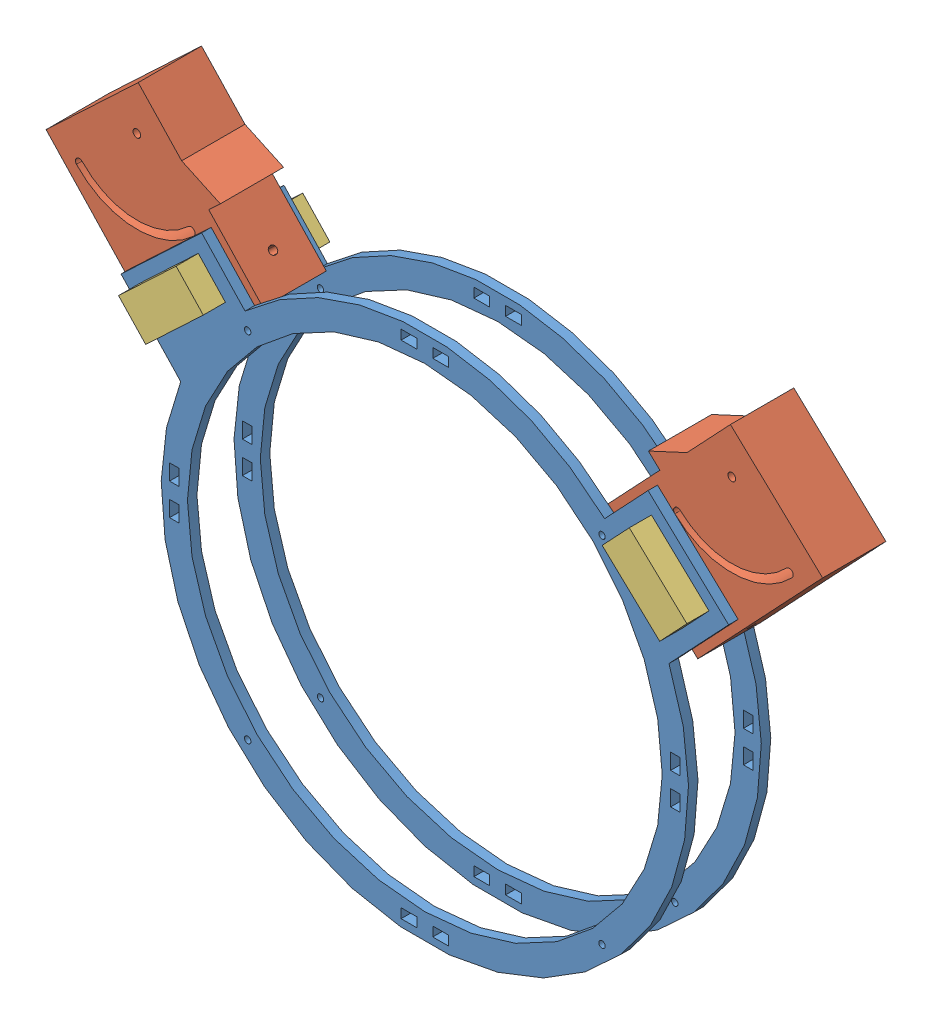
SolidWorks assembly Aramado, configuration Predeterminado. Lengths in mm.
Overall size (490.65 380.63 80.02).
6 component instances, 3 part files, 11 mates.
Components (placement in the parent):
- Anillo acrilico-1: Anillo acrilico [Predeterminado] at (-159.8874 164.786 383.9345) size (383.93 333.2 6)
- anclaje para base_1-3: anclaje para base_1 [Predeterminado] at (-195.9783 155.136 343.9345) x (0 0 -1) z (-0.685795 0.727795 0) size (40 90 115)
- Anillo acrilico-2: Anillo acrilico [Predeterminado] at (-159.8874 164.786 337.9345) size (383.93 333.2 6)
- anclaje para base_1-4: anclaje para base_1 [Predeterminado] at (184.5852 155.136 383.9345) x (0 0 1) z (0.685795 0.727795 0) size (40 90 115)
- Pieza prisionera-1: Pieza prisionera [Predeterminado] at (-166.2782 137.2738 323.9284) x (-0.685795 0.727795 0) z (0 0 1) size (25 50 80)
- Pieza prisionera-2: Pieza prisionera [Predeterminado] at (165.5199 127.2527 323.9108) x (0.685795 0.727795 0) z (0 0 1) size (25 50 80)
Mates (geometry in assembly coordinates):
- Coincidente5: coincident aligned: line of Anillo acrilico-1 through (-131.7078 126.3866 383.9345) axis (-0.685795 0.727795 0); line of anclaje para base_1-3 through (-131.7078 126.3866 383.9345) axis (-0.685795 0.727795 0)
- Coincidente6: coincident aligned: line of Anillo acrilico-1 through (-185.2424 110.2917 383.9345) axis (0.685795 -0.727795 0); line of anclaje para base_1-3 through (-185.2424 110.2917 383.9345) axis (0.685795 -0.727795 0)
- Coincidente7: coincident aligned: line of Anillo acrilico-1 through (-168.0975 92.0969 383.9345) axis (0.727795 0.685795 0); line of anclaje para base_1-3 through (-168.0975 92.0969 383.9345) axis (0.727795 0.685795 0)
- Coincidente15: coincident anti-aligned: line of Anillo acrilico-1 through (156.7044 92.0969 383.9345) axis (-0.727795 0.685795 0); line of anclaje para base_1-4 through (120.3147 126.3866 383.9345) axis (0.727795 -0.685795 0)
- Coincidente16: coincident anti-aligned: line of Anillo acrilico-1 through (173.8493 110.2917 383.9345) axis (-0.685795 -0.727795 0); line of anclaje para base_1-4 through (156.7044 92.0969 383.9345) axis (0.685795 0.727795 0)
- Coincidente17: coincident anti-aligned: line of anclaje para base_1-3 through (-185.2424 110.2917 343.9345) axis (0.727795 0.685795 0); line of Anillo acrilico-2 through (-148.8527 144.5815 343.9345) axis (-0.727795 -0.685795 0)
- Coincidente18: coincident anti-aligned: line of anclaje para base_1-3 through (-148.8527 144.5815 343.9345) axis (0.685795 -0.727795 0); line of Anillo acrilico-2 through (-131.7078 126.3866 343.9345) axis (-0.685795 0.727795 0)
- Coincidente21: coincident anti-aligned: plane of anclaje para base_1-4 through (120.3147 126.3866 343.9345) normal (0.685795 0.727795 0); plane of Pieza prisionera-2 through (156.7044 92.0969 403.9108) normal (-0.685795 -0.727795 0)
- Coincidente22: coincident anti-aligned: plane of anclaje para base_1-4 through (137.4595 144.5815 343.9345) normal (0.727795 -0.685795 0); plane of Pieza prisionera-2 through (120.3147 126.3866 403.9108) normal (-0.727795 0.685795 0)
- Coincidente25: coincident anti-aligned: plane of anclaje para base_1-3 through (-131.7078 126.3866 383.9346) normal (-0.685795 0.727795 0); plane of Pieza prisionera-1 through (-131.7078 126.3866 403.9284) normal (0.685795 -0.727795 0)
- Coincidente26: coincident anti-aligned: plane of anclaje para base_1-3 through (-168.0975 92.0969 383.9346) normal (0.727795 0.685795 0); plane of Pieza prisionera-1 through (-168.0975 92.0969 403.9284) normal (-0.727795 -0.685795 0)
